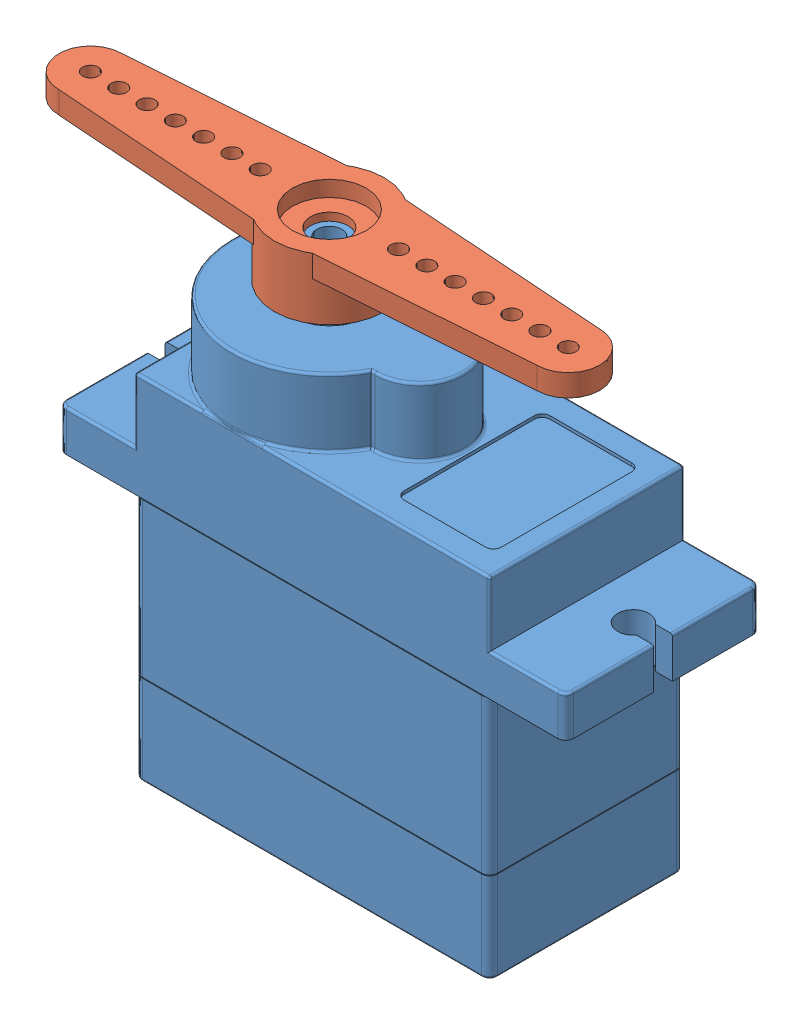
SolidWorks assembly microservoAssembly, configuration Default. Lengths in mm.
Overall size (38.45 31.3 12.5).
2 component instances, 2 part files, 2 mates.
Components (placement in the parent):
- microservoSG90-1: microservoSG90 [Default] at (7.8094 3.3655 26.0766) size (32.3 29.8 12.5)
- microservoArm-1: microservoArm [A2] at (2.7094 34.6655 26.0766) x (-1 0 0.000751) z (0.000751 0 1) size (34.4 3.9 7)
Mates (geometry in assembly coordinates):
- Concentric1: concentric anti-aligned: circle of microservoSG90-1; circle of microservoArm-1
- Coincident2: coincident anti-aligned: plane of microservoSG90-1 through (2.7094 33.1655 26.0766) normal (0 1 0); plane of microservoArm-1 through (2.7094 33.1655 26.0766) normal (0 -1 0)
